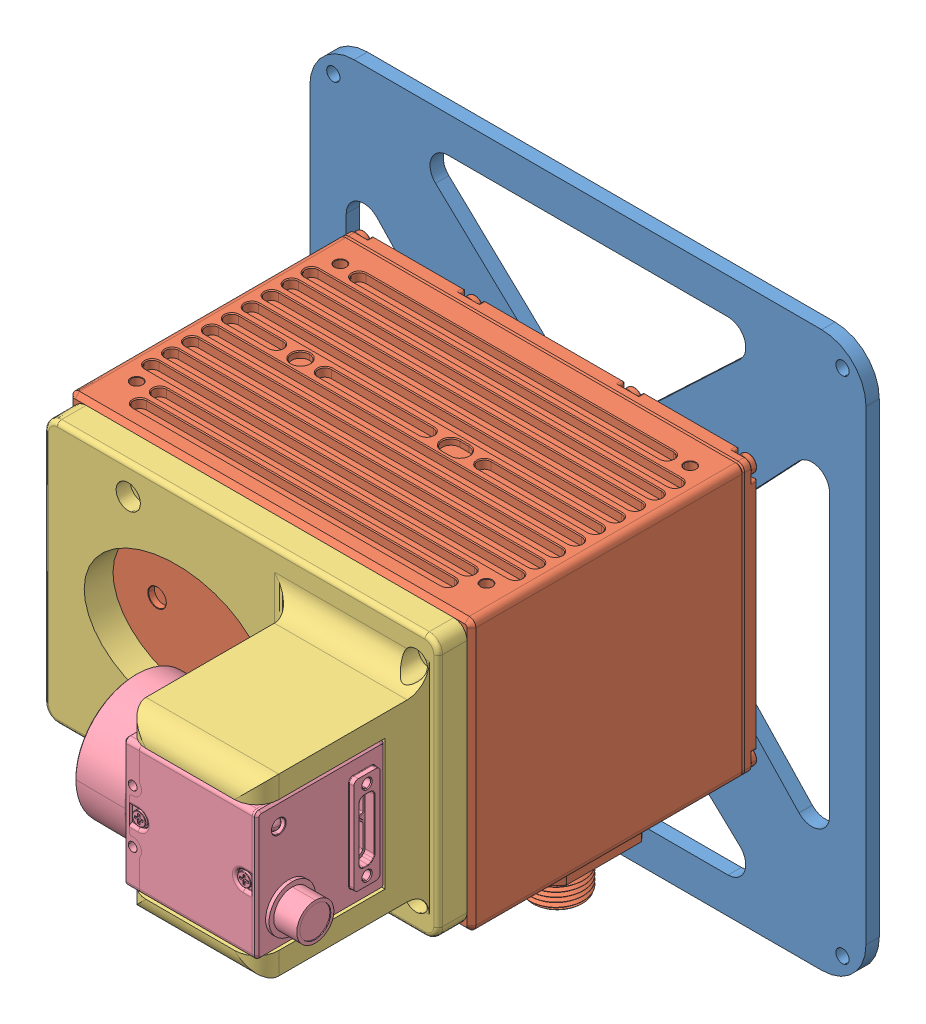
SolidWorks assembly flying_LIVO, configuration 默认. Lengths in mm.
Overall size (125.6 125.3 113.3).
7 component instances, 5 part files, 9 mates.
Components (placement in the parent):
- fly_base-1: fly_base [默认] at (-71.8765 52.4809 124.1) size (125.6 125.3 3)
- AVIA-1: AVIA [Default] at (-81.3765 -48.6691 111.2) x (1 0 0) z (0 -1 0) size (91.02 64.8 76.07)
  - Livox_Avia_shell_FOV.stp-1: Livox_Avia_shell_FOV.stp [Default] at origin size (1207.64 1420.81 1420.81)
    - LIVOX_AVIA.stp-1: LIVOX_AVIA.stp [Default] at origin size (91.02 64.8 76.07)
    - LIVOX_AVIA_FOV.stp-1: LIVOX_AVIA_FOV.stp [Default] at (19.97 48.3 -38.5) x (0 0 -1) z (1 0 0) size (1420.81 1420.81 1123.13) (hidden)
- T_cam_livox-1: T_cam_livox [默认] at (-9.0765 -10.1691 198.4) x (0 1 0) z (0 0 -1) size (59.2 89 45.5)
- FL2-020-R0-1: FL2-020-R0 [Default] at (9.3053 -10.1691 222.9) x (0 -1 0) z (-1 0 0) size (29 29 47.76)
Mates (geometry in assembly coordinates):
- 同心2: concentric anti-aligned: circle of fly_base-1; cylinder of AVIA-1/Livox_Avia_shell_FOV.stp-1/LIVOX_AVIA.stp-1 through (-41.5765 -33.1691 131.688) axis (0 0 -1) radius 1.25
- 同心5: concentric aligned: cylinder of fly_base-1 through (-41.5765 12.8309 127.1) axis (0 0 -1) radius 1.5; cylinder of AVIA-1/Livox_Avia_shell_FOV.stp-1/LIVOX_AVIA.stp-1 through (-41.5765 12.8309 131.688) axis (0 0 -1) radius 1.25
- 重合1: coincident anti-aligned: plane of fly_base-1 through (-71.8765 52.4809 127.1) normal (0 0 1); plane of AVIA-1/Livox_Avia_shell_FOV.stp-1/LIVOX_AVIA.stp-1 through (-16.0765 -10.1691 127.1) normal (0 0 -1)
- 同心6: concentric aligned: cylinder of T_cam_livox-1 through (23.4235 12.8309 191.9) axis (0 0 1) radius 1.6; cylinder of AVIA-1/Livox_Avia_shell_FOV.stp-1/LIVOX_AVIA.stp-1 through (23.4235 12.8309 187.312) axis (0 0 1) radius 1.25
- 重合2: coincident anti-aligned: plane of AVIA-1/Livox_Avia_shell_FOV.stp-1/LIVOX_AVIA.stp-1 through (-16.0765 -10.1691 191.9) normal (0 0 1); plane of T_cam_livox-1 through (-9.0765 -10.1691 191.9) normal (0 0 -1)
- 同心7: concentric aligned: cylinder of AVIA-1/Livox_Avia_shell_FOV.stp-1/LIVOX_AVIA.stp-1 through (-41.5765 12.8309 187.312) axis (0 0 1) radius 1.25; cylinder of T_cam_livox-1 through (-41.5765 12.8309 191.9) axis (0 0 1) radius 1.6
- 同心8: concentric aligned: cylinder of T_cam_livox-1 through (23.1235 -10.1691 308.4) axis (0 0 -1) radius 1.6; circle of FL2-020-R0-1
- 重合3: coincident anti-aligned: plane of T_cam_livox-1 through (-9.0765 -10.1691 208.4) normal (0 0 1); plane of FL2-020-R0-1 through (-0.0765 3.3309 208.4) normal (0 0 -1)
- 同心9: concentric aligned: cylinder of T_cam_livox-1 through (-0.5765 -0.1691 308.4) axis (0 0 -1) radius 1.6; cylinder of FL2-020-R0-1 through (-0.5765 -0.1691 208.4) axis (0 0 -1) radius 1.5
